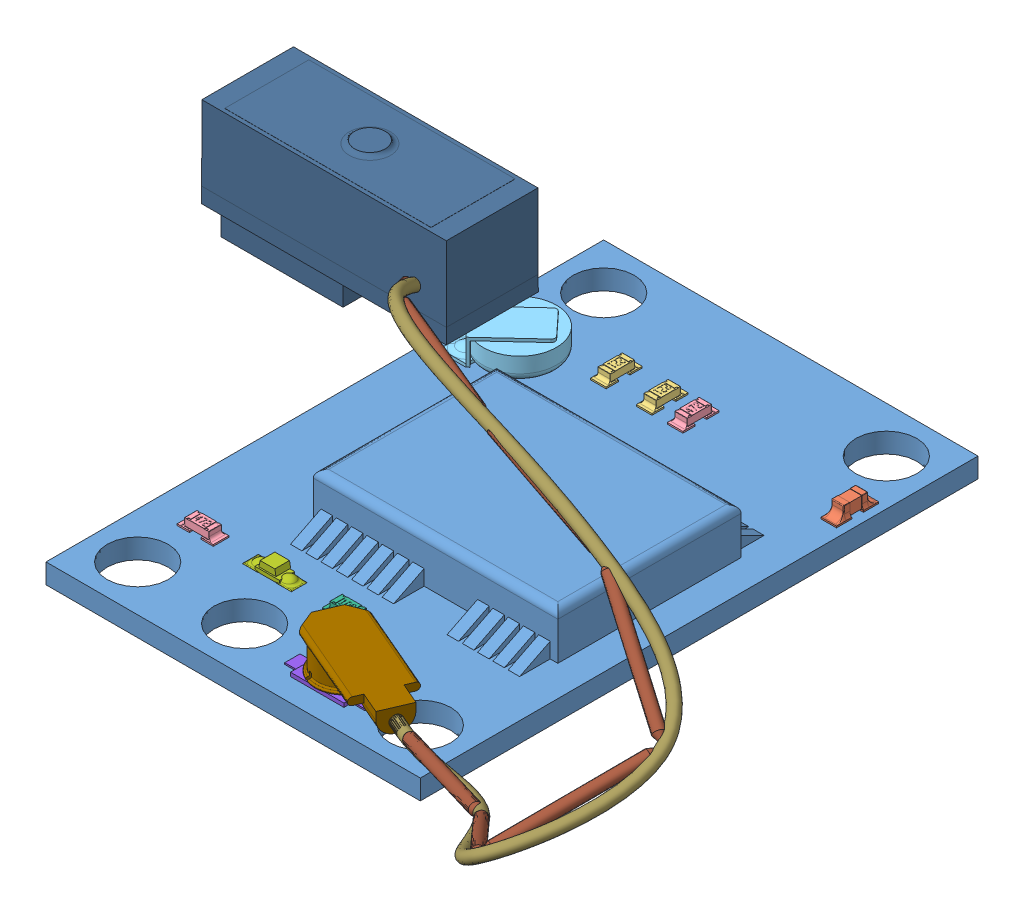
SolidWorks assembly ublox NEO-6M, configuration Predeterminado. Lengths in mm.
Overall size (44.14 22.61 47.2).
20 component instances, 12 part files, 43 mates.
Components (placement in the parent):
- GPS_pcb-1: GPS_pcb [Predeterminado] at (-12.25 0 -1.25) size (24.5 4.3 36.5)
- GPS_cap-1: GPS_cap [Default] at (-1.008 1.3577 -12.1193) x (0 0 1) z (-1 0 0) size (2.76 0.9 1.12)
- GPS_res221-1: GPS_res221 [Default] at (-13.49 1.3 -12.319) x (0 0 1) z (-1 0 0) size (2.36 0.61 1.03)
- GPS_res472-1: GPS_res472 [Default] at (-11.4616 1.3 -12.319) x (0 0 -1) z (1 0 0) size (2.36 0.61 1.03)
- GPS_res221-4: GPS_res221 [Default] at (-16.49 1.3 -12.319) x (0 0 1) z (-1 0 0) size (2.36 0.61 1.03)
- GPS_battery-1: GPS_battery [Predeterminado] at (-14.7943 1.2998 13.0331) x (0.679996 0 0.733216) z (0 1 0) size (6.1 6.1 1.74)
- GPS_res472-2: GPS_res472 [Default] at (-20.7044 1.6833 10.5205) size (2.36 0.61 1.03)
- GPS_res100-1: GPS_res100 [Default] at (-11.2066 1.6833 10.5205) size (2.36 0.61 1.03)
- GPS_led-1: GPS_led [Default] at (-15.9936 1.6512 10.5305) size (3.2 0.76 1.08)
- GPS_connector-1: GPS_connector [Predeterminado] at (-0.2977 1.3 -0.3039) x (1 0 0) z (0 1 0) size (5.25 3.5 2.05)
- Antenna_connector-1: Antenna_connector [Predeterminado] at (-5.7969 1.55 3.7956) x (0.39525 0 -0.918574) z (0 1 0) size (3.81 9.5 2.31)
- Antenna-1: Antenna [Predeterminado] at (-20.328 17.5 11.3294) x (0 0 1) z (0 1 0) size (6.22 16.22 7.61)
- Rod-1: Rod [Predeterminado] at (-23.5794 6.8157 -8.9286) x (-0.155546 -0.786176 0.598107) z (-0.836468 0.426909 0.343613) size (0.75 10 0.75)
- Rod-2: Rod [Predeterminado] at (-4.3569 25.2884 9.6584) x (-0.567186 -0.286615 0.772108) z (0.274393 0.818169 0.50528) size (0.75 10 0.75)
- Rod-3: Rod [Predeterminado] at (25.3098 14.2264 38.4524) x (0.419656 -0.893569 0.159443) z (0.651883 0.174471 -0.737976) size (0.75 10 0.75)
- Rod-4: Rod [Predeterminado] at (-16.4235 22.522 11.448) x (-0.252412 -0.368125 0.894859) z (0.124185 0.904832 0.407257) size (0.75 10 0.75)
- Rod-5: Rod [Predeterminado] at (24.1727 16.8105 3.7163) x (0.502062 -0.852492 -0.145572) z (-0.792267 -0.385882 -0.472661) size (0.75 10 0.75)
- Rod-6: Rod [Predeterminado] at (-24.216 22.0522 1.8461) x (0.339577 0.460513 -0.820131) z (0.11516 -0.885739 -0.449671) size (0.75 10 0.75)
- Rod-7: Rod [Predeterminado] at (-15.7114 0.3341 8.3861) x (0.370322 0.155439 -0.915806) z (0.226179 -0.971316 -0.073402) size (0.75 10 0.75)
- cable-1: cable [Predeterminado] at (-20.328 17.5 6.7993) x (0 -1 0) z (0 0 1) size (18.54 33.59 26.04)
Mates (geometry in assembly coordinates):
- Coincidente2: coincident: plane of GPS_pcb-1 through (-12.25 0 -1.25) normal (0 -1 0); plane of assembly through (0 0 0) normal (0 1 0)
- Coincidente3: coincident: line of GPS_pcb-1 through (15 -17.5 4.3) axis (0 1 0); plane of assembly
- Coincidente4: coincident: line of GPS_pcb-1 through (0 0 17) axis (0 0 -1); plane of assembly
- Paralelo2: parallel aligned: line of GPS_pcb-1 through (-24.5 1.3 -19.5) axis (0 0 1); line of GPS_cap-1 through (-1.516 1.3577 -11.7383) axis (0 0 1)
- Distancia4: distance = 0.5 mm: plane of GPS_cap-1 through (-0.5 1.4577 -13.5003) normal (1 0 0); line of GPS_pcb-1 through (0 1.3 17) axis (0 0 -1)
- Distancia5: distance = 6 mm: line of GPS_cap-1 through (-0.5 1.3577 -13.5003) axis (-1 0 0); line of GPS_pcb-1 through (0 1.3 -19.5) axis (-1 0 0)
- Coincidente9: coincident anti-aligned: plane of GPS_pcb-1 through (-12.25 1.3 -1.25) normal (0 1 0); plane of GPS_res221-1 through (-13.49 1.3 -12.319) normal (0 -1 0)
- Perpendicular1: perpendicular: line of GPS_pcb-1 through (0 1.3 -19.5) axis (-1 0 0); line of GPS_res221-1 through (-12.98 1.3 -12.7) axis (0 0 -1)
- Distancia6: distance = 14 mm: line of GPS_res221-1 through (-14 1.3 -13.5) axis (0 0 1); line of GPS_pcb-1 through (0 1.3 17) axis (0 0 -1)
- Distancia8: distance = 6 mm: line of GPS_res221-1 through (-12.98 1.3 -13.5) axis (-1 0 0); line of GPS_pcb-1 through (0 1.3 -19.5) axis (-1 0 0)
- Coincidente14: coincident anti-aligned: plane of GPS_pcb-1 through (-12.25 1.3 -1.25) normal (0 1 0); plane of GPS_res472-1 through (-11.4616 1.3 -12.319) normal (0 -1 0)
- Paralelo5: parallel aligned: line of GPS_res221-1 through (-12.98 1.3 -11.138) axis (0 0 -1); line of GPS_res472-1 through (-10.9516 1.3 -11.138) axis (0 0 -1)
- Coincidente19: coincident aligned: line of GPS_res221-1 through (-14 1.3 -11.138) axis (1 0 0); line of GPS_res472-1 through (-11.9716 1.3 -11.138) axis (1 0 0)
- Distancia11: distance = 3 mm: line of GPS_res472-1 through (-10.9516 1.3 -11.138) axis (0 0 -1); line of GPS_res221-1 through (-13.89 1.905 -11.849) axis (0 0 -1)
- Paralelo6: parallel anti-aligned: line of GPS_pcb-1 through (-24.5 1.3 -19.5) axis (0 0 1); line of GPS_battery-1 through (-23.5 1.2998 -7.769) axis (0 0 -1)
- Distancia12: distance = 1 mm: line of GPS_battery-1 through (-23.5 1.2998 -7.769) axis (0 0 -1); line of GPS_pcb-1 through (-24.5 1.3 -19.5) axis (0 0 1)
- Distancia13: distance = 6.5 mm: line of GPS_battery-1 through (-23.4413 1.4998 -13.0031) axis (1 0 0); line of GPS_pcb-1 through (0 1.3 -19.5) axis (-1 0 0)
- Coincidente24: coincident anti-aligned: line of GPS_res100-1 through (-10.0256 1.6833 10.0105) axis (-1 0 0); line of GPS_led-1 through (-14.6483 1.6833 10.0105) axis (1 0 0)
- Coincidente25: coincident aligned: line of GPS_res472-2 through (-19.5234 1.6833 10.0105) axis (-1 0 0); line of GPS_res100-1 through (-11.5876 1.6833 10.0105) axis (-1 0 0)
- Distancia14: distance = 7 mm: line of GPS_res100-1 through (-10.0256 1.6833 10.0105) axis (-1 0 0); line of GPS_pcb-1 through (-24.5 1.3 17) axis (1 0 0)
- Distancia15: distance = 5 mm: line of GPS_res472-2 through (-19.5234 1.7833 11.0305) axis (0 0 -1); line of GPS_pcb-1 through (-24.5 1.3 -19.5) axis (0 0 1)
- Distancia16: distance = 2 mm: line of GPS_res472-2 through (-19.5234 1.7833 11.0305) axis (0 0 -1); line of GPS_led-1 through (-17.5243 1.7233 10.6355) axis (0 0 1)
- Distancia17: distance = 2 mm: line of GPS_res100-1 through (-12.3876 1.7833 10.0105) axis (0 0 1); cylinder of GPS_led-1 through (-14.4629 1.6433 10.0105) axis (0 0 1) radius 0.08
- Coincidente26: coincident anti-aligned: plane of GPS_pcb-1 through (-12.25 1.3 -1.25) normal (0 1 0); plane of GPS_connector-1 through (-0.2977 1.3 -0.3039) normal (0 -1 0)
- Distancia18: distance = 5 mm: line of GPS_connector-1 through (-10 1.3 12) axis (1 0 0); line of GPS_pcb-1 through (-24.5 1.3 17) axis (1 0 0)
- Distancia19: distance = 10 mm: line of GPS_connector-1 through (-10 1.3 15.5) axis (0 0 -1); line of GPS_pcb-1 through (0 1.3 17) axis (0 0 -1)
- Concéntrica1: concentric aligned: cylinder of GPS_connector-1 through (-8.25 3.35 13.75) axis (0 -1 0) radius 1.5; cylinder of Antenna_connector-1 through (-8.25 3.35 13.75) axis (0 -1 0) radius 1.5
- Coincidente29: coincident anti-aligned: circle of GPS_connector-1; plane of Antenna_connector-1 through (-5.7969 3.35 3.7956) normal (0 -1 0)
- Paralelo8: parallel anti-aligned: plane of GPS_pcb-1 through (-12.25 4.3 -1.25) normal (0 1 0); plane of Antenna-1 through (-20.328 15 11.3294) normal (0 -1 0)
- Coincidente41: coincident: point of Antenna-1; point of Rod-1
- Coincidente42: coincident: point of Rod-1; point of Rod-6
- Coincidente43: coincident: point of Antenna_connector-1; point of Rod-7
- Coincidente44: coincident: point of Rod-3; point of Rod-7
- Coincidente45: coincident: point of Rod-4; point of Rod-6
- Coincidente46: coincident: point of Rod-2; point of Rod-4
- Coincidente47: coincident: point of Rod-3; point of Rod-5
- Coincidente48: coincident: point of Rod-2; point of Rod-5
- EnPosición2: in place: plane of ? through (-10.3239 23.7718 8.9025) normal (-0.99517 0 0.098165); plane of ? through (-11.0941 0 1.0943) normal (-0.99517 0 0.098165); moOrthogonalPlaneRef_w of ? through (-10.3239 23.7718 8.9025) normal (-0.99517 0 0.098165); unknown of ?; plane of ? through (-10.3239 23.7718 8.9025) normal (-0.99517 0 0.098165); plane of ? through (-11.0941 0 1.0943) normal (0.098165 0 0.99517); plane of Antenna-1 through (-8.5 22.4 6.7993) normal (0 0 1); unknown of cable-1
- Coincidente49: coincident aligned: plane of Antenna-1; plane of cable-1
- Coincidente50: coincident aligned: moOrthogonalPlaneRef_w of Antenna-1; plane of cable-1
- Coincidente51: coincident anti-aligned: moOrthogonalPlaneRef_w of Antenna-1 through (-20.328 17.5 6.7993) normal (0 1 0); plane of cable-1
- Distancia20: distance = 15 mm aligned: plane of GPS_pcb-1 through (-12.25 0 -1.25) normal (0 -1 0); plane of Antenna-1 through (-20.328 15 11.3294) normal (0 -1 0)
- Coincidente51: coincident aligned: plane of GPS_pcb-1 through (-24.5 1.3 17) normal (-1 0 0); plane of Antenna-1 through (-24.5 22.4 0.7993) normal (-1 0 0)
